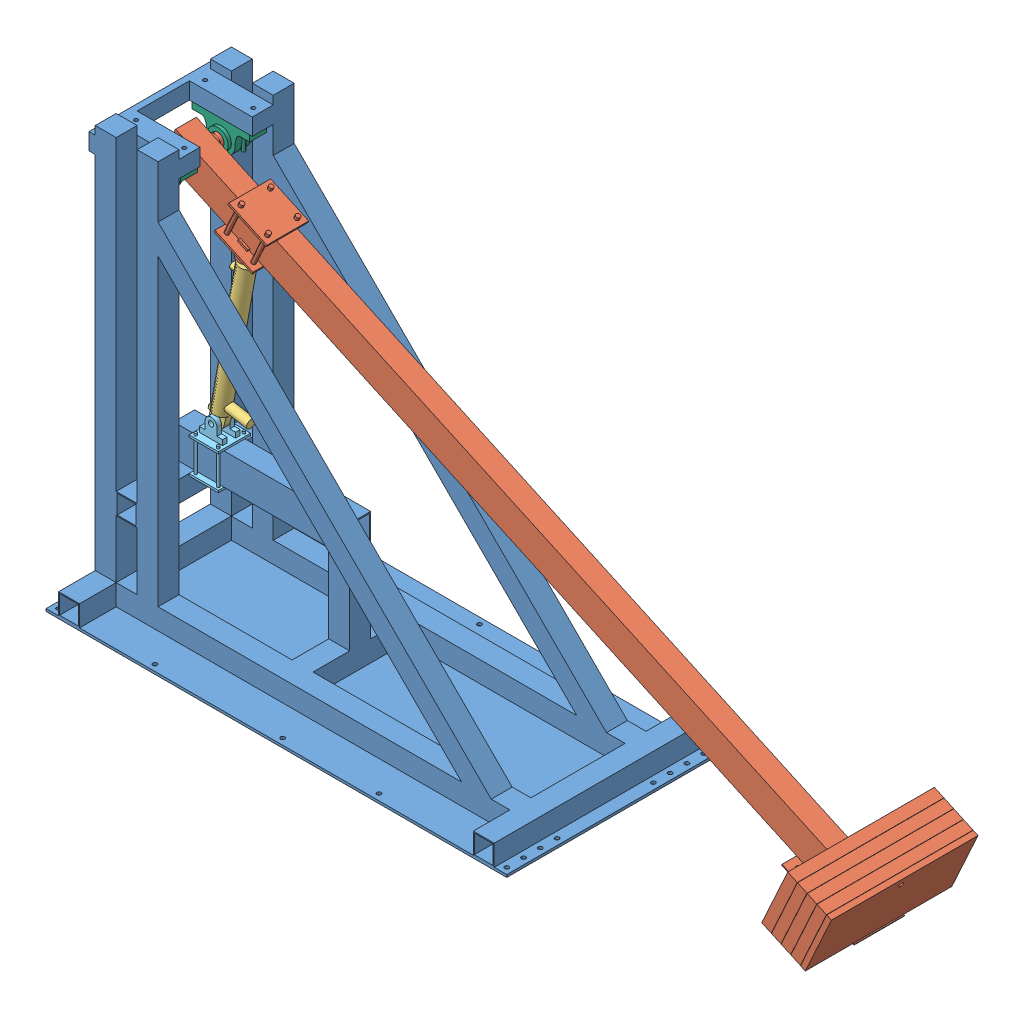
SolidWorks assembly 0 Experimental_arm_assembly (FEM), configuration Position 1. Lengths in mm.
Overall size (3604.53 1989.89 1000).
7 component instances, 6 part files, 26 mates.
Components (placement in the parent):
- Main_part-1: Main_part [Default] at (50 -1740 225)
- Arm_part-1: Arm_part [Default] x (0.909344 -0.416045 0) z (0 0 1)
- Cyl_hus_part-1: Cyl_hus_part [Default] at (120 -1040 0) x (-0.984199 0.177067 0) z (0 0 -1)
- Cyl_rod_part-1: Cyl_rod_part [Default] at (256.6959 -280.1986 0) x (0.984199 -0.177067 0) z (0 0 1)
- Cyl_mounting_bottom_part-1: Cyl_mounting_bottom_part [Low version] at (120 -1263 0)
- Bearing_house_SKF_SNA_513-611-1: Bearing_house_SKF_SNA_513-611 [Default] at (0 0 -165) x (-1 0 0) z (0 0 1)
- Bearing_house_SKF_SNA_513-611-2: Bearing_house_SKF_SNA_513-611 [Default] at (0 0 165) x (-1 0 0) z (0 0 1)
Mates (geometry in assembly coordinates):
- Coincident2: coincident aligned: plane of Arm_part-1 through (0 0 0) normal (0 0 1); plane of assembly through (0 0 0) normal (0 0 1)
- Coincident3: coincident anti-aligned: plane of Cyl_hus_part-1 through (120 -1040 0) normal (0 0 -1); plane of assembly through (0 0 0) normal (0 0 1)
- Coincident4: coincident aligned: plane of Cyl_rod_part-1 through (256.6959 -280.1986 0) normal (0 0 1); plane of assembly through (0 0 0) normal (0 0 1)
- Coincident5: coincident anti-aligned: plane of Cyl_hus_part-1; plane of Cyl_rod_part-1
- Coincident6: coincident aligned: plane of Main_part-1 through (50 -1740 0) normal (0 0 1); plane of assembly through (0 0 0) normal (0 0 1)
- Concentric2: concentric aligned: cylinder of Arm_part-1 through (256.6959 -280.1986 42) axis (0 0 -1) radius 12.5; cylinder of Cyl_rod_part-1 through (256.6959 -280.1986 15) axis (0 0 -1) radius 12.5
- LimitDistance1: limit distance = 500 mm anti-aligned: plane of Cyl_hus_part-1 through (263.2953 -342.3492 0) normal (-0.177067 -0.984199 0); plane of Cyl_rod_part-1 through (174.7617 -834.4485 0) normal (0.177067 0.984199 0)
- Coincident8: coincident aligned: plane of Cyl_mounting_bottom_part-1 through (120 -1263 0) normal (0 0 1); plane of assembly through (0 0 0) normal (0 0 1)
- Distance7: distance = 1040 mm aligned: plane of Cyl_mounting_bottom_part-1 through (120 -1040 0) normal (0 1 0); plane of assembly through (0 0 0) normal (0 1 0)
- Distance3: distance = 1740 mm aligned: plane of Main_part-1 through (50 -1740 225) normal (0 1 0); plane of assembly through (0 0 0) normal (0 1 0)
- Distance4: distance = 50 mm: point of assembly; plane of Main_part-1 through (50 -1740 225) normal (1 0 0)
- Cyl_pos_high: concentric anti-aligned: cylinder of Cyl_hus_part-1 through (350 -1010 -15) axis (0 0 1) radius 12.5; cylinder of Cyl_mounting_bottom_part-1 through (500 -1010 42) axis (0 0 -1) radius 12.5
- Cyl_pos_3: concentric anti-aligned: cylinder of Cyl_hus_part-1 through (349.9068 -1020 -15) axis (0 0 1) radius 12.5; cylinder of Cyl_mounting_bottom_part-1 through (500 -1010 42) axis (0 0 -1) radius 12.5
- Pos 2: distance = 350 mm: plane of ? through (350 -1213 0) normal (1 0 0)
- Pos 1: distance = 120 mm: point of assembly; plane of Cyl_mounting_bottom_part-1 through (120 -1263 0) normal (1 0 0)
- Pos 1_con: concentric anti-aligned: cylinder of Cyl_hus_part-1 through (120 -1040 -15) axis (0 0 1) radius 12.5; cylinder of Cyl_mounting_bottom_part-1 through (120 -1040 42) axis (0 0 -1) radius 12.5
- Pos 3: distance = 500 mm: plane of ? through (500 -1213 0) normal (1 0 0)
- Coincident9: coincident anti-aligned: plane of Main_part-1 through (150 80 -125) normal (0 -1 0); plane of Bearing_house_SKF_SNA_513-611-1 through (-137.5 80 -125) normal (0 1 0)
- Parallel1: parallel aligned: plane of Bearing_house_SKF_SNA_513-611-1 through (0 0 -165) normal (0 0 1); plane of assembly through (0 0 0) normal (0 0 1)
- Parallel2: parallel aligned: plane of Bearing_house_SKF_SNA_513-611-2 through (0 0 165) normal (0 0 1); plane of assembly through (0 0 0) normal (0 0 1)
- Coincident12: coincident anti-aligned: plane of Main_part-1 through (150 80 -125) normal (0 -1 0); plane of Bearing_house_SKF_SNA_513-611-2 through (-137.5 80 205) normal (0 1 0)
- Coincident13: coincident aligned: plane of Main_part-1 through (50 -1740 -125) normal (0 0 1); plane of Bearing_house_SKF_SNA_513-611-1 through (92.5 32.0281 -125) normal (0 0 1)
- Coincident14: coincident aligned: plane of Main_part-1 through (50 -1740 125) normal (0 0 -1); plane of Bearing_house_SKF_SNA_513-611-2 through (92.5 32.0281 125) normal (0 0 -1)
- Coincident15: coincident: plane of Bearing_house_SKF_SNA_513-611-1; point of assembly
- Distance8: distance = 50 mm aligned: plane of Bearing_house_SKF_SNA_513-611-2; plane of Main_part-1 through (50 -1640 325) normal (-1 0 0)
- Concentric3: concentric aligned: cylinder of Arm_part-1 through (0 0 215) axis (0 0 -1) radius 30; cylinder of Bearing_house_SKF_SNA_513-611-2 through (0 0 205) axis (0 0 -1) radius 30
